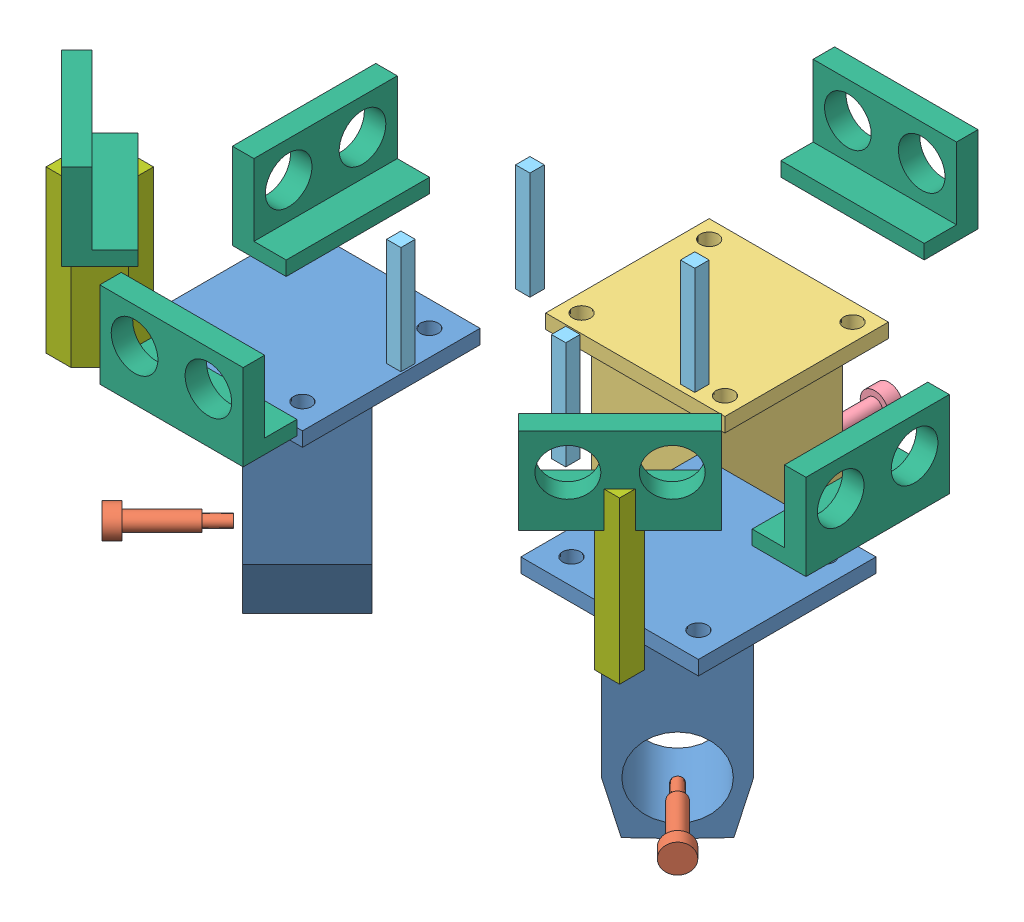
SolidWorks assembly milestone1_3dprints_Final_Assem_v2, configuration Default. Lengths in mm.
Overall size (266.12 155.39 218.29).
163 component instances, 34 part files, 103 mates.
Components (placement in the parent):
- WheelAsm-1: WheelAsm [Default] at (146.9069 -186.0529 168.258) x (-0.210422 -0.954696 0.210422) z (-0.707107 0 -0.707107) size (63.86 60.79 27.6) (hidden)
  - WheelBase-2: WheelBase [Default] at (4.9023 2.731 55.3836) x (1 0 0) z (0 -1 0) size (56.86 5 54.96)
  - BasePlacer-1: BasePlacer [Default] at (4.9023 2.731 58.8836) x (1 0 0) z (0 -1 0) size (28 10 28)
  - RubberWheel-1: RubberWheel [Default] at (4.9023 26.7901 57.8836) x (1 0 0) z (0 -0.999594 -0.028494) size (19 12.5 12.5)
  - RubberWheel-2: RubberWheel [Default] at (-17.9792 10.1657 57.8836) x (0.309017 0.951057 0) z (0.95067 -0.308892 -0.028494) size (19 12.5 12.5)
  - RubberWheel-3: RubberWheel [Default] at (-9.2392 -16.7332 57.8836) x (-0.809017 0.587785 0) z (0.587547 0.808689 -0.028494) size (19 12.5 12.5)
  - RubberWheel-4: RubberWheel [Default] at (19.0439 -16.7332 57.8836) x (-0.809017 -0.587785 0) z (-0.587547 0.808689 -0.028494) size (19 12.5 12.5)
  - RubberWheel-5: RubberWheel [Default] at (27.7839 10.1657 57.8836) x (0.309017 -0.951057 0) z (-0.95067 -0.308892 -0.028494) size (19 12.5 12.5)
  - Rivet-1: Rivet [Default] at (4.9023 -21.269 54.8836) x (1 0 0) z (0 1 0) size (7.46 6.8 7.46)
  - Rivet-2: Rivet [Default] at (27.7277 -4.6854 54.8836) x (0.309017 0.951057 0) z (-0.951057 0.309017 0) size (7.46 6.8 7.46)
  - Rivet-3: Rivet [Default] at (19.0092 22.1474 54.8836) x (-0.809017 0.587785 0) z (-0.587785 -0.809017 0) size (7.46 6.8 7.46)
  - Rivet-4: Rivet [Default] at (-9.2045 22.1474 54.8836) x (-0.809017 -0.587785 0) z (0.587785 -0.809017 0) size (7.46 6.8 7.46)
  - Rivet-5: Rivet [Default] at (-17.923 -4.6854 54.8836) x (0.309017 -0.951057 0) z (0.951057 0.309017 0) size (7.46 6.8 7.46)
  - WheelBase-6: WheelBase [Default] at (4.9023 2.731 67.3836) x (-1 0 0) z (0 1 0) size (56.86 5 54.96)
  - RubberWheel-16: RubberWheel [Default] at (4.9023 -21.3281 69.8836) size (19 12.5 12.5)
  - RubberWheel-17: RubberWheel [Default] at (27.7839 -4.7037 69.8836) x (0.309017 0.951057 0) z (0 0 1) size (19 12.5 12.5)
  - RubberWheel-18: RubberWheel [Default] at (19.0439 22.1953 69.8836) x (-0.809017 0.587785 0) z (0 0 1) size (19 12.5 12.5)
  - RubberWheel-19: RubberWheel [Default] at (-9.2392 22.1953 69.8836) x (-0.809017 -0.587785 0) z (0 0 1) size (19 12.5 12.5)
  - RubberWheel-20: RubberWheel [Default] at (-17.9792 -4.7037 69.8836) x (0.309017 -0.951057 0) z (0 0 1) size (19 12.5 12.5)
  - Rivet-16: Rivet [Default] at (-9.2045 -16.6854 72.8836) x (-0.985624 0.168955 0) z (0.168955 0.985624 0) size (7.46 6.8 7.46)
  - Rivet-17: Rivet [Default] at (19.0092 -16.6854 72.8836) x (-0.46526 -0.885174 0) z (-0.885174 0.46526 0) size (7.46 6.8 7.46)
  - Rivet-18: Rivet [Default] at (27.7277 10.1474 72.8836) x (0.698077 -0.716022 0) z (-0.716022 -0.698077 0) size (7.46 6.8 7.46)
  - Rivet-19: Rivet [Default] at (4.9023 26.731 72.8836) x (0.896695 0.442648 0) z (0.442648 -0.896695 0) size (7.46 6.8 7.46)
  - Rivet-20: Rivet [Default] at (-17.923 10.1474 72.8836) x (-0.143889 0.989594 0) z (0.989594 0.143889 0) size (7.46 6.8 7.46)
  - ShaftConnector-1: ShaftConnector [Default] at (4.9023 2.731 48.8836) x (1 0 0) z (0 -1 0) size (14 27.6 14)
  - Part7^WheelAsm-1: Part7^WheelAsm [Default] at origin (virtual)
  - Part8^WheelAsm-1: Part8^WheelAsm [Default] at origin (virtual)
  - M3HexNut-1: M3HexNut [Default] at (13.9956 7.981 72.8836) x (1 0 0) z (0 0 -1) size (5 5 5)
  - M3HexNut-2: M3HexNut [Default] at (-4.1909 7.981 72.8836) x (-0.5 0.866025 0) z (0 0 -1) size (5 5 5)
  - M3HexNut-3: M3HexNut [Default] at (4.9023 -7.769 72.8836) x (-0.5 -0.866025 0) z (0 0 -1) size (5 5 5)
  - M3HexNut-4: M3HexNut [Default] at (4.9023 -7.769 54.8836) size (5 5 5)
  - M3HexNut-5: M3HexNut [Default] at (13.9956 7.981 54.8836) x (-0.5 0.866025 0) z (0 0 1) size (5 5 5)
  - M3HexNut-6: M3HexNut [Default] at (-4.1909 7.981 54.8836) x (-0.5 -0.866025 0) z (0 0 1) size (5 5 5)
- WheelAsm-2: WheelAsm [Default] at (14.2994 -187.213 -82.1798) x (-0.999988 0.004806 0) z (0 0 1) size (63.86 60.79 27.6) (hidden)
  - WheelBase-2: WheelBase [Default] at (4.9023 2.731 55.3836) x (1 0 0) z (0 -1 0) size (56.86 5 54.96)
  - BasePlacer-1: BasePlacer [Default] at (4.9023 2.731 58.8836) x (1 0 0) z (0 -1 0) size (28 10 28)
  - RubberWheel-1: RubberWheel [Default] at (4.9023 26.7901 57.8836) x (1 0 0) z (0 -0.999594 -0.028494) size (19 12.5 12.5)
  - RubberWheel-2: RubberWheel [Default] at (-17.9792 10.1657 57.8836) x (0.309017 0.951057 0) z (0.95067 -0.308892 -0.028494) size (19 12.5 12.5)
  - RubberWheel-3: RubberWheel [Default] at (-9.2392 -16.7332 57.8836) x (-0.809017 0.587785 0) z (0.587547 0.808689 -0.028494) size (19 12.5 12.5)
  - RubberWheel-4: RubberWheel [Default] at (19.0439 -16.7332 57.8836) x (-0.809017 -0.587785 0) z (-0.587547 0.808689 -0.028494) size (19 12.5 12.5)
  - RubberWheel-5: RubberWheel [Default] at (27.7839 10.1657 57.8836) x (0.309017 -0.951057 0) z (-0.95067 -0.308892 -0.028494) size (19 12.5 12.5)
  - Rivet-1: Rivet [Default] at (4.9023 -21.269 54.8836) x (1 0 0) z (0 1 0) size (7.46 6.8 7.46)
  - Rivet-2: Rivet [Default] at (27.7277 -4.6854 54.8836) x (0.309017 0.951057 0) z (-0.951057 0.309017 0) size (7.46 6.8 7.46)
  - Rivet-3: Rivet [Default] at (19.0092 22.1474 54.8836) x (-0.809017 0.587785 0) z (-0.587785 -0.809017 0) size (7.46 6.8 7.46)
  - Rivet-4: Rivet [Default] at (-9.2045 22.1474 54.8836) x (-0.809017 -0.587785 0) z (0.587785 -0.809017 0) size (7.46 6.8 7.46)
  - Rivet-5: Rivet [Default] at (-17.923 -4.6854 54.8836) x (0.309017 -0.951057 0) z (0.951057 0.309017 0) size (7.46 6.8 7.46)
  - WheelBase-6: WheelBase [Default] at (4.9023 2.731 67.3836) x (-1 0 0) z (0 1 0) size (56.86 5 54.96)
  - RubberWheel-16: RubberWheel [Default] at (4.9023 -21.3281 69.8836) size (19 12.5 12.5)
  - RubberWheel-17: RubberWheel [Default] at (27.7839 -4.7037 69.8836) x (0.309017 0.951057 0) z (0 0 1) size (19 12.5 12.5)
  - RubberWheel-18: RubberWheel [Default] at (19.0439 22.1953 69.8836) x (-0.809017 0.587785 0) z (0 0 1) size (19 12.5 12.5)
  - RubberWheel-19: RubberWheel [Default] at (-9.2392 22.1953 69.8836) x (-0.809017 -0.587785 0) z (0 0 1) size (19 12.5 12.5)
  - RubberWheel-20: RubberWheel [Default] at (-17.9792 -4.7037 69.8836) x (0.309017 -0.951057 0) z (0 0 1) size (19 12.5 12.5)
  - Rivet-16: Rivet [Default] at (-9.2045 -16.6854 72.8836) x (-0.985624 0.168955 0) z (0.168955 0.985624 0) size (7.46 6.8 7.46)
  - Rivet-17: Rivet [Default] at (19.0092 -16.6854 72.8836) x (-0.46526 -0.885174 0) z (-0.885174 0.46526 0) size (7.46 6.8 7.46)
  - Rivet-18: Rivet [Default] at (27.7277 10.1474 72.8836) x (0.698077 -0.716022 0) z (-0.716022 -0.698077 0) size (7.46 6.8 7.46)
  - Rivet-19: Rivet [Default] at (4.9023 26.731 72.8836) x (0.896695 0.442648 0) z (0.442648 -0.896695 0) size (7.46 6.8 7.46)
  - Rivet-20: Rivet [Default] at (-17.923 10.1474 72.8836) x (-0.143889 0.989594 0) z (0.989594 0.143889 0) size (7.46 6.8 7.46)
  - ShaftConnector-1: ShaftConnector [Default] at (4.9023 2.731 48.8836) x (1 0 0) z (0 -1 0) size (14 27.6 14)
  - Part7^WheelAsm-1: Part7^WheelAsm [Default] at origin (virtual)
  - Part8^WheelAsm-1: Part8^WheelAsm [Default] at origin (virtual)
  - M3HexNut-1: M3HexNut [Default] at (13.9956 7.981 72.8836) x (1 0 0) z (0 0 -1) size (5 5 5)
  - M3HexNut-2: M3HexNut [Default] at (-4.1909 7.981 72.8836) x (-0.5 0.866025 0) z (0 0 -1) size (5 5 5)
  - M3HexNut-3: M3HexNut [Default] at (4.9023 -7.769 72.8836) x (-0.5 -0.866025 0) z (0 0 -1) size (5 5 5)
  - M3HexNut-4: M3HexNut [Default] at (4.9023 -7.769 54.8836) size (5 5 5)
  - M3HexNut-5: M3HexNut [Default] at (13.9956 7.981 54.8836) x (-0.5 0.866025 0) z (0 0 1) size (5 5 5)
  - M3HexNut-6: M3HexNut [Default] at (-4.1909 7.981 54.8836) x (-0.5 -0.866025 0) z (0 0 1) size (5 5 5)
- WheelAsm-3: WheelAsm [Default] at (-127.298 -191.8955 165.739) x (0.457087 0.762983 0.457087) z (0.707107 0 -0.707107) size (63.86 60.79 27.6) (hidden)
  - WheelBase-2: WheelBase [Default] at (4.9023 2.731 55.3836) x (1 0 0) z (0 -1 0) size (56.86 5 54.96)
  - BasePlacer-1: BasePlacer [Default] at (4.9023 2.731 58.8836) x (1 0 0) z (0 -1 0) size (28 10 28)
  - RubberWheel-1: RubberWheel [Default] at (4.9023 26.7901 57.8836) x (1 0 0) z (0 -0.999594 -0.028494) size (19 12.5 12.5)
  - RubberWheel-2: RubberWheel [Default] at (-17.9792 10.1657 57.8836) x (0.309017 0.951057 0) z (0.95067 -0.308892 -0.028494) size (19 12.5 12.5)
  - RubberWheel-3: RubberWheel [Default] at (-9.2392 -16.7332 57.8836) x (-0.809017 0.587785 0) z (0.587547 0.808689 -0.028494) size (19 12.5 12.5)
  - RubberWheel-4: RubberWheel [Default] at (19.0439 -16.7332 57.8836) x (-0.809017 -0.587785 0) z (-0.587547 0.808689 -0.028494) size (19 12.5 12.5)
  - RubberWheel-5: RubberWheel [Default] at (27.7839 10.1657 57.8836) x (0.309017 -0.951057 0) z (-0.95067 -0.308892 -0.028494) size (19 12.5 12.5)
  - Rivet-1: Rivet [Default] at (4.9023 -21.269 54.8836) x (1 0 0) z (0 1 0) size (7.46 6.8 7.46)
  - Rivet-2: Rivet [Default] at (27.7277 -4.6854 54.8836) x (0.309017 0.951057 0) z (-0.951057 0.309017 0) size (7.46 6.8 7.46)
  - Rivet-3: Rivet [Default] at (19.0092 22.1474 54.8836) x (-0.809017 0.587785 0) z (-0.587785 -0.809017 0) size (7.46 6.8 7.46)
  - Rivet-4: Rivet [Default] at (-9.2045 22.1474 54.8836) x (-0.809017 -0.587785 0) z (0.587785 -0.809017 0) size (7.46 6.8 7.46)
  - Rivet-5: Rivet [Default] at (-17.923 -4.6854 54.8836) x (0.309017 -0.951057 0) z (0.951057 0.309017 0) size (7.46 6.8 7.46)
  - WheelBase-6: WheelBase [Default] at (4.9023 2.731 67.3836) x (-1 0 0) z (0 1 0) size (56.86 5 54.96)
  - RubberWheel-16: RubberWheel [Default] at (4.9023 -21.3281 69.8836) size (19 12.5 12.5)
  - RubberWheel-17: RubberWheel [Default] at (27.7839 -4.7037 69.8836) x (0.309017 0.951057 0) z (0 0 1) size (19 12.5 12.5)
  - RubberWheel-18: RubberWheel [Default] at (19.0439 22.1953 69.8836) x (-0.809017 0.587785 0) z (0 0 1) size (19 12.5 12.5)
  - RubberWheel-19: RubberWheel [Default] at (-9.2392 22.1953 69.8836) x (-0.809017 -0.587785 0) z (0 0 1) size (19 12.5 12.5)
  - RubberWheel-20: RubberWheel [Default] at (-17.9792 -4.7037 69.8836) x (0.309017 -0.951057 0) z (0 0 1) size (19 12.5 12.5)
  - Rivet-16: Rivet [Default] at (-9.2045 -16.6854 72.8836) x (-0.985624 0.168955 0) z (0.168955 0.985624 0) size (7.46 6.8 7.46)
  - Rivet-17: Rivet [Default] at (19.0092 -16.6854 72.8836) x (-0.46526 -0.885174 0) z (-0.885174 0.46526 0) size (7.46 6.8 7.46)
  - Rivet-18: Rivet [Default] at (27.7277 10.1474 72.8836) x (0.698077 -0.716022 0) z (-0.716022 -0.698077 0) size (7.46 6.8 7.46)
  - Rivet-19: Rivet [Default] at (4.9023 26.731 72.8836) x (0.896695 0.442648 0) z (0.442648 -0.896695 0) size (7.46 6.8 7.46)
  - Rivet-20: Rivet [Default] at (-17.923 10.1474 72.8836) x (-0.143889 0.989594 0) z (0.989594 0.143889 0) size (7.46 6.8 7.46)
  - ShaftConnector-1: ShaftConnector [Default] at (4.9023 2.731 48.8836) x (1 0 0) z (0 -1 0) size (14 27.6 14)
  - Part7^WheelAsm-1: Part7^WheelAsm [Default] at origin (virtual)
  - Part8^WheelAsm-1: Part8^WheelAsm [Default] at origin (virtual)
  - M3HexNut-1: M3HexNut [Default] at (13.9956 7.981 72.8836) x (1 0 0) z (0 0 -1) size (5 5 5)
  - M3HexNut-2: M3HexNut [Default] at (-4.1909 7.981 72.8836) x (-0.5 0.866025 0) z (0 0 -1) size (5 5 5)
  - M3HexNut-3: M3HexNut [Default] at (4.9023 -7.769 72.8836) x (-0.5 -0.866025 0) z (0 0 -1) size (5 5 5)
  - M3HexNut-4: M3HexNut [Default] at (4.9023 -7.769 54.8836) size (5 5 5)
  - M3HexNut-5: M3HexNut [Default] at (13.9956 7.981 54.8836) x (-0.5 0.866025 0) z (0 0 1) size (5 5 5)
  - M3HexNut-6: M3HexNut [Default] at (-4.1909 7.981 54.8836) x (-0.5 -0.866025 0) z (0 0 1) size (5 5 5)
- 6V Motor Spin-1: 6V Motor Spin [Default] at (27.2733 -240.3712 60.9424) x (-0.886104 0.457845 -0.072098) z (0.080946 -0.000295 -0.996718) size (29.63 28.32 78.39) (hidden)
  - Motor no spinny boi-1: Motor no spinny boi [Default] at (39.6165 36.3483 7.7453) x (0.997226 -0.015871 -0.072721) z (0.072098 -0.036799 0.996718) size (24.4 25.49 66.9)
  - Motor spinny boi-1: Motor spinny boi [Default] at (39.6165 36.3483 7.7453) x (0.547957 0.836461 -0.008754) z (0.072098 -0.036799 0.996718) size (3.95 3.95 13.05)
- DC Motor 12V-1: DC Motor 12V [Predeterminado] at (-50.6883 -189.9205 96.5577) x (0.707107 0 0.707107) z (-0.707107 0 0.707107) size (28.03 28 53.5) (hidden)
  - Carcaça12V-1: Carcaça12V [Predeterminado] at (0 0 24.0663) size (28.03 28 32.04)
  - Bucha12V-1: Bucha12V [Predeterminado] at (0 0 26.0163) x (0.994754 0.102295 0) z (0 0 1) size (7 7 0.5)
  - Mancal12V-1: Mancal12V [Predeterminado] at (0 0 -2.9337) x (-1 0 0) z (0 0 -1) size (27.69 28 8)
  - Terminal12V-1: Terminal12V [Predeterminado] at (0 -11.5 -3.9337) x (1 0 0) z (0 1 0) size (2.9 10 0.4)
  - Terminal12V-2: Terminal12V [Predeterminado] at (0 11.5 -3.9337) x (1 0 0) z (0 1 0) size (2.9 10 0.4)
  - Eixo12V-1: Eixo12V [Predeterminado] at (0 0 39.5663) x (-0.33009 -0.943949 0) z (0 0 1) size (21 20.89 51)
  - Enrolamento12V-1: Enrolamento12V [Predeterminado] at (-5.1702 1.808 12.5663) x (0.33009 0.943949 0) z (0 0 1) size (10 3 20)
  - Enrolamento12V-2: Enrolamento12V [Predeterminado] at (1.0194 -5.3815 12.5663) x (-0.982529 -0.186108 0) z (0 0 1) size (10 3 20)
  - Enrolamento12V-3: Enrolamento12V [Predeterminado] at (4.1509 3.5736 12.5663) x (0.652439 -0.757841 0) z (0 0 1) size (10 3 20)
- DC Motor 12V-2: DC Motor 12V [Predeterminado] at (71.1645 -189.9205 98.266) x (-0.300546 0.905176 0.300546) z (0.707107 0 0.707107) size (28.03 28 53.5) (hidden)
  - Carcaça12V-1: Carcaça12V [Predeterminado] at (0 0 24.0663) size (28.03 28 32.04)
  - Bucha12V-1: Bucha12V [Predeterminado] at (0 0 26.0163) x (0.994754 0.102295 0) z (0 0 1) size (7 7 0.5)
  - Mancal12V-1: Mancal12V [Predeterminado] at (0 0 -2.9337) x (-1 0 0) z (0 0 -1) size (27.69 28 8)
  - Terminal12V-1: Terminal12V [Predeterminado] at (0 -11.5 -3.9337) x (1 0 0) z (0 1 0) size (2.9 10 0.4)
  - Terminal12V-2: Terminal12V [Predeterminado] at (0 11.5 -3.9337) x (1 0 0) z (0 1 0) size (2.9 10 0.4)
  - Eixo12V-1: Eixo12V [Predeterminado] at (0 0 39.5663) x (-0.33009 -0.943949 0) z (0 0 1) size (21 20.89 51)
  - Enrolamento12V-1: Enrolamento12V [Predeterminado] at (-5.1702 1.808 12.5663) x (0.33009 0.943949 0) z (0 0 1) size (10 3 20)
  - Enrolamento12V-2: Enrolamento12V [Predeterminado] at (1.0194 -5.3815 12.5663) x (-0.982529 -0.186108 0) z (0 0 1) size (10 3 20)
  - Enrolamento12V-3: Enrolamento12V [Predeterminado] at (4.1509 3.5736 12.5663) x (0.652439 -0.757841 0) z (0 0 1) size (10 3 20)
- Acrylic Plate (square 12 inch) cut version-1: Acrylic Plate (square 12 inch) cut version [Default] at (9.384 -134.5485 57.0478) size (203.2 6.35 203.2) (hidden)
- ScoopClawAssembly-1: ScoopClawAssembly [Default] at (-135.2234 -155.5644 109.464) size (171.3 138.74 218) (hidden)
  - Scooper-1: Scooper [Default] at (144.6073 0.6103 138.0053) x (1 0 0) z (0 0.793599 0.608442) size (152.65 142.24 11.1)
  - Scooper_Base-1: Scooper_Base [Default] at (144.6073 -61.534 72.0438) size (162.56 95.25 144.78)
  - HC-SR04-UltrasonicSensor v7-2: HC-SR04-UltrasonicSensor v7 [Default] at (144.5683 -48.834 48.9638) x (-1 0 0) z (0 0 1) size (45.45 26.2 17.79)
  - Hinge_Joint-1: Hinge_Joint [Default] at (126.8273 46.416 67.8239) x (0 0.774266 0.63286) z (1 0 0) size (8.89 8.89 40.64)
  - Hinge_Part1-1: Hinge_Part1 [Default] at (144.6073 33.716 67.8239) size (35.56 18.62 12.7)
  - Hinge_Part2-1: Hinge_Part2 [Default] at (144.6073 54.4789 74.0056) x (1 0 0) z (0 0.608442 -0.793599) size (25.4 16.08 12.7)
  - 6V Motor Spin-1: 6V Motor Spin [Default] at (231.6559 14.0419 25.1949) x (-0.072098 -0.103157 0.992049) z (-0.996718 0.044149 -0.067847) size (29.63 28.32 78.39) (hidden)
    - Motor no spinny boi-1: Motor no spinny boi [Default] at (39.6165 36.3483 7.7453) x (0.997226 -0.015871 -0.072721) z (0.072098 -0.036799 0.996718) size (24.4 25.49 66.9)
    - Motor spinny boi-1: Motor spinny boi [Default] at (39.6165 36.3483 7.7453) x (0.547957 0.836461 -0.008754) z (0.072098 -0.036799 0.996718) size (3.95 3.95 13.05)
  - Motor Support-1: Motor Support [Default] at (195.4073 27.366 67.8239) size (38.1 54.53 38.1)
- ArduinoMega-1: ArduinoMega [Default] at (9.3459 -119.6895 95.1478) x (0 0 -1) z (0 -1 0) size (107.95 53.42 12.95) (hidden)
- 12V Motor Support-1: 12V Motor Support [Default] at (76.6872 -189.9205 103.7887) x (0.707107 0 0.707107) z (-0.707107 0 0.707107) size (88.99 74.11 88.99)
- 12V Motor Support-2: 12V Motor Support [Default] at (-56.211 -189.9205 102.0804) x (0.707107 0 -0.707107) z (0.707107 0 0.707107) size (88.99 74.11 88.99)
- OmniWheel_Connection Piece-2: OmniWheel_Connection Piece [Default] at (89.7093 -189.9205 116.8107) x (-0.693991 0.19171 0.693991) z (0.707107 0 0.707107) size (10.16 10.16 33.02)
- OmniWheel_Connection Piece-3: OmniWheel_Connection Piece [Default] at (-69.2613 -189.9205 115.1307) x (0.707107 0 0.707107) z (-0.707107 0 0.707107) size (10.16 10.16 33.02)
- 6V Motor Support-1: 6V Motor Support [Default] at (9.384 -189.9205 22.5038) x (0 0 -1) z (1 0 0) size (57.91 74.11 63.5)
- 6V Wheel Connector-1: 6V Wheel Connector [Default] at (9.384 -189.9205 -6.1182) x (-0.104526 0.994522 0) z (0 0 -1) size (10.16 10.16 32.26)
- LED Height Booster-1: LED Height Booster [Default] at (38.594 -83.7485 59.5878) x (-1 0 0) z (0 0 1) size (5.08 38.1 5.08)
- LED Height Booster-2: LED Height Booster [Default] at (-19.826 -121.8485 105.3042) size (5.08 38.1 5.08)
- LED Height Booster-3: LED Height Booster [Default] at (38.594 -83.7485 105.3042) x (-1 0 0) z (0 0 1) size (5.08 38.1 5.08)
- LED Height Booster-4: LED Height Booster [Default] at (-19.826 -121.8485 59.5878) size (5.08 38.1 5.08)
- LightBoard Localization-2: LightBoard Localization [Default] at (9.384 -83.7485 82.4478) x (-1 0 0) z (0 0 -1) size (101.6 13.49 50.8) (hidden)
- HC-SR04-UltrasonicSensor v7-1: HC-SR04-UltrasonicSensor v7 [Default] at (-40.996 -204.3985 158.4278) x (-1 0 0) z (0 0 1) size (45.45 26.2 17.79) (hidden)
- HC-SR04-UltrasonicSensor v7-2: HC-SR04-UltrasonicSensor v7 [Default] at (59.764 -204.3985 158.4278) x (-1 0 0) z (0 0 1) size (45.45 26.2 17.79) (hidden)
- US_Support-2: US_Support [Default] at (103.364 -123.1185 67.2078) x (0 0 -1) z (1 0 0) size (50.8 30.48 19.05)
- US_Support-3: US_Support [Default] at (-84.596 -123.1185 67.2078) x (0 0 1) z (-1 0 0) size (50.8 30.48 19.05)
- BatteryRemodeled-2: BatteryRemodeled [Default] at (34.784 -76.1031 -0.1022) x (-1 0 0) z (0 0 1) size (64.52 53.39 25.65) (hidden)
- US_Support-4: US_Support [Default] at (9.384 -123.1185 -36.9322) x (-1 0 0) z (0 0 -1) size (50.8 30.48 19.05)
- US_Support-5: US_Support [Default] at (-47.766 -123.1185 151.0278) size (50.8 30.48 19.05)
- HC-SR04-UltrasonicSensor v7-3: HC-SR04-UltrasonicSensor v7 [Default] at (98.064 -110.4185 67.1688) x (0 0 1) z (1 0 0) size (45.45 26.2 17.79) (hidden)
- HC-SR04-UltrasonicSensor v7-4: HC-SR04-UltrasonicSensor v7 [Default] at (9.345 -110.4185 -31.6322) x (1 0 0) z (0 0 -1) size (45.45 26.2 17.79) (hidden)
- HC-SR04-UltrasonicSensor v7-5: HC-SR04-UltrasonicSensor v7 [Default] at (-79.296 -110.4185 67.1688) x (0 0 -1) z (-1 0 0) size (45.45 26.2 17.79) (hidden)
- corner_support-1: corner_support [Default] at (-82.691 -128.1985 149.1228) size (19.05 57.15 19.05)
- US_Support-6: US_Support [Default] at (-84.1338 -78.6685 150.386) x (0.707107 0 0.707107) z (-0.707107 0 0.707107) size (50.8 30.48 19.05)
- HC-SR04-UltrasonicSensor v7-6: HC-SR04-UltrasonicSensor v7 [Default] at (-80.3586 -65.9685 146.6659) x (-0.707107 0 -0.707107) z (-0.707107 0 0.707107) size (45.45 26.2 17.79) (hidden)
- HC-SR04-UltrasonicSensor v7-7: HC-SR04-UltrasonicSensor v7 [Default] at (-47.805 -110.4185 145.7278) x (-1 0 0) z (0 0 1) size (45.45 26.2 17.79) (hidden)
- corner_support-2: corner_support [Default] at (101.459 -128.1985 149.1228) x (0 0 -1) z (1 0 0) size (19.05 57.15 19.05)
- US_Support-7: US_Support [Default] at (102.9017 -78.6685 150.386) x (0.707107 0 -0.707107) z (0.707107 0 0.707107) size (50.8 30.48 19.05)
- HC-SR04-UltrasonicSensor v7-8: HC-SR04-UltrasonicSensor v7 [Default] at (99.1265 -65.9685 146.6659) x (-0.707107 0 0.707107) z (0.707107 0 0.707107) size (45.45 26.2 17.79) (hidden)
Mates (geometry in assembly coordinates):
- Coincident3: coincident: plane of Acrylic Plate (square 12 inch) cut version-1 through (9.384 -128.1985 57.0478) normal (0 1 0); plane of ScoopClawAssembly-1/Scooper_Base-1 through (9.384 -128.1985 181.5078) normal (0 -1 0)
- Coincident4: coincident: plane of Acrylic Plate (square 12 inch) cut version-1 through (-92.216 -128.1985 158.6478) normal (0 0 1); plane of ScoopClawAssembly-1/Scooper_Base-1 through (9.384 -217.0985 158.6478) normal (0 0 -1)
- Distance4: distance = 0.508 mm: plane of ScoopClawAssembly-1/Scooper_Base-1 through (9.384 -121.8485 181.5078) normal (0 1 0); plane of ArduinoMega-1 through (-17.3622 -121.3405 44.3478) normal (0 -1 0)
- Distance6: distance = 12.7 mm: plane of ArduinoMega-1 through (36.054 -121.3405 44.3478) normal (0 0 -1); plane of ScoopClawAssembly-1/Scooper_Base-1 through (41.134 -121.8485 57.0478) normal (0 0 -1)
- Distance7: distance = 5.08 mm: plane of ArduinoMega-1 through (36.054 -121.3405 145.9478) normal (1 0 0); plane of ScoopClawAssembly-1/Scooper_Base-1 through (41.134 -166.2985 158.6478) normal (1 0 0)
- Coincident23: coincident: plane of Acrylic Plate (square 12 inch) cut version-1 through (9.384 -134.5485 57.0478) normal (0 -1 0); plane of 12V Motor Support-1 through (76.6872 -134.5485 103.7887) normal (0 1 0)
- Coincident29: coincident: plane of Acrylic Plate (square 12 inch) cut version-1 through (9.384 -134.5485 57.0478) normal (0 -1 0); plane of 12V Motor Support-2 through (-56.211 -134.5485 102.0804) normal (0 1 0)
- Concentric1: concentric: cylinder of DC Motor 12V-1/Carcaça12V-1 through (-47.1996 -189.9205 93.069) axis (-0.707107 0 0.707107) radius 14; cylinder of 12V Motor Support-2 through (-134.5188 -189.9205 180.3882) axis (0.707107 0 -0.707107) radius 13.9872
- Coincident31: coincident: plane of DC Motor 12V-1/Carcaça12V-1 through (-67.7057 -189.9205 113.5751) normal (-0.707107 0 0.707107); plane of 12V Motor Support-2 through (-54.2353 -139.6285 127.0455) normal (-0.707107 0 0.707107)
- Coincident32: coincident: plane of DC Motor 12V-2/Carcaça12V-1 through (88.1819 -189.9205 115.2834) normal (0.707107 0 0.707107); plane of 12V Motor Support-1 through (74.7115 -139.6285 128.7538) normal (0.707107 0 0.707107)
- Concentric2: concentric: cylinder of DC Motor 12V-2/Carcaça12V-1 through (67.6758 -189.9205 94.7773) axis (0.707107 0 0.707107) radius 14; cylinder of 12V Motor Support-1 through (-1.6206 -189.9205 25.4808) axis (0.707107 0 0.707107) radius 13.9872
- Concentric4: concentric: circle of WheelAsm-1/ShaftConnector-1; circle of DC Motor 12V-2/Eixo12V-1
- Coincident36: coincident: plane of WheelAsm-1/ShaftConnector-1 through (89.9497 -189.9205 117.0512) normal (-0.707107 0 -0.707107); plane of DC Motor 12V-2/Carcaça12V-1 through (89.9497 -189.9205 117.0512) normal (0.707107 0 0.707107)
- Concentric8: concentric: circle of WheelAsm-1/ShaftConnector-1; circle of OmniWheel_Connection Piece-2
- Coincident39: coincident: plane of WheelAsm-1/ShaftConnector-1 through (109.4658 -189.9205 136.5673) normal (0.707107 0 0.707107); plane of OmniWheel_Connection Piece-2 through (109.4658 -189.9205 136.5673) normal (-0.707107 0 -0.707107)
- Distance9: distance = 69.85 mm: plane of ScoopClawAssembly-1/Scooper_Base-1 through (-22.366 -128.1985 158.6478) normal (-1 0 0); plane of Acrylic Plate (square 12 inch) cut version-1 through (-92.216 -128.1985 158.6478) normal (-1 0 0)
- Concentric9: concentric: circle of WheelAsm-3/ShaftConnector-1; circle of DC Motor 12V-1/Eixo12V-1
- Coincident42: coincident: plane of WheelAsm-3/ShaftConnector-1 through (-89.0179 -189.9205 134.8873) normal (-0.707107 0 0.707107); plane of OmniWheel_Connection Piece-3 through (-89.0179 -189.9205 134.8873) normal (0.707107 0 -0.707107)
- Concentric10: concentric: circle of WheelAsm-3/ShaftConnector-1; circle of OmniWheel_Connection Piece-3
- Coincident43: coincident: plane of DC Motor 12V-1/Bucha12V-1 through (-69.2613 -189.9205 115.1307) normal (-0.707107 0 0.707107); plane of OmniWheel_Connection Piece-3 through (-69.2613 -189.9205 115.1307) normal (0.707107 0 -0.707107)
- Coincident45: coincident: plane of Acrylic Plate (square 12 inch) cut version-1 through (9.384 -134.5485 57.0478) normal (0 -1 0); plane of 6V Motor Support-1 through (9.384 -134.5485 22.5038) normal (0 1 0)
- Concentric11: concentric: circle of 6V Motor Spin-1/Motor no spinny boi-1; circle of 6V Motor Support-1
- Coincident48: coincident: plane of 6V Motor Spin-1/Motor no spinny boi-1 through (9.384 -189.9205 -2.8962) normal (0 0 -1); plane of 6V Motor Support-1 through (28.434 -139.6285 -2.8962) normal (0 0 -1)
- Concentric13: concentric: circle of WheelAsm-2/ShaftConnector-1; circle of 6V Motor Support-1
- Coincident49: coincident: plane of WheelAsm-2/ShaftConnector-1 through (9.384 -189.9205 -5.6962) normal (0 0 1); plane of 6V Motor Spin-1/Motor no spinny boi-1 through (9.384 -189.9205 -5.6962) normal (0 0 -1)
- Concentric14: concentric: circle of WheelAsm-2/ShaftConnector-1; circle of 6V Wheel Connector-1
- Coincident51: coincident: plane of 6V Motor Spin-1/Motor spinny boi-1 through (9.2246 -188.4038 -5.9462) normal (-0.104526 0.994522 0); plane of 6V Wheel Connector-1 through (9.2246 -188.4038 -16.0242) normal (0.104526 -0.994522 0)
- Coincident52: coincident: plane of WheelAsm-2/ShaftConnector-1 through (9.384 -189.9205 -33.2962) normal (0 0 -1); plane of 6V Wheel Connector-1 through (9.384 -189.9205 -33.2962) normal (0 0 1)
- Distance13: distance = 38.1 mm: plane of 6V Motor Support-1 through (41.134 -134.5485 -6.4522) normal (0 0 -1); plane of Acrylic Plate (square 12 inch) cut version-1 through (-92.216 -128.1985 -44.5522) normal (0 0 -1)
- Distance15: distance = 69.85 mm: plane of 6V Motor Support-1 through (41.134 -134.5485 -6.4522) normal (1 0 0); plane of Acrylic Plate (square 12 inch) cut version-1 through (110.984 -128.1985 158.6478) normal (1 0 0)
- Coincident73: coincident: plane of ScoopClawAssembly-1/Scooper_Base-1 through (9.384 -121.8485 181.5078) normal (0 1 0); plane of LED Height Booster-1 through (38.594 -121.8485 59.5878) normal (0 -1 0)
- Coincident74: coincident: plane of ScoopClawAssembly-1/Scooper_Base-1 through (41.134 -121.8485 57.0478) normal (0 0 -1); plane of LED Height Booster-1 through (41.134 -121.8485 57.0478) normal (0 0 -1)
- Coincident75: coincident: plane of ScoopClawAssembly-1/Scooper_Base-1 through (41.134 -166.2985 158.6478) normal (1 0 0); plane of LED Height Booster-1 through (41.134 -121.8485 62.1278) normal (1 0 0)
- Coincident76: coincident: plane of ScoopClawAssembly-1/Scooper_Base-1 through (41.134 -121.8485 57.0478) normal (0 0 -1); plane of LED Height Booster-4 through (-22.366 -83.7485 57.0478) normal (0 0 -1)
- Coincident77: coincident: plane of ScoopClawAssembly-1/Scooper_Base-1 through (9.384 -121.8485 181.5078) normal (0 1 0); plane of LED Height Booster-4 through (-19.826 -121.8485 59.5878) normal (0 -1 0)
- Coincident78: coincident: plane of ScoopClawAssembly-1/Scooper_Base-1 through (-22.366 -128.1985 158.6478) normal (-1 0 0); plane of LED Height Booster-4 through (-22.366 -83.7485 62.1278) normal (-1 0 0)
- Coincident79: coincident: plane of ScoopClawAssembly-1/Scooper_Base-1 through (9.384 -121.8485 181.5078) normal (0 1 0); plane of LED Height Booster-3 through (38.594 -121.8485 105.3042) normal (0 -1 0)
- Coincident80: coincident: plane of LED Height Booster-1 through (41.134 -121.8485 62.1278) normal (1 0 0); plane of LED Height Booster-3 through (41.134 -121.8485 107.8442) normal (1 0 0)
- Distance21: distance = 55.4736 mm: plane of LED Height Booster-3 through (41.134 -121.8485 102.7642) normal (0 0 -1); plane of ScoopClawAssembly-1/Motor Support-1 through (41.134 -123.1185 158.2378) normal (0 0 -1)
- Coincident82: coincident: plane of LED Height Booster-2 through (-22.366 -83.7485 102.7642) normal (0 0 -1); plane of LED Height Booster-3 through (41.134 -121.8485 102.7642) normal (0 0 -1)
- Coincident83: coincident: plane of ScoopClawAssembly-1/Scooper_Base-1 through (9.384 -121.8485 181.5078) normal (0 1 0); plane of LED Height Booster-2 through (-19.826 -121.8485 105.3042) normal (0 -1 0)
- Coincident84: coincident: plane of ScoopClawAssembly-1/Scooper_Base-1 through (-22.366 -128.1985 158.6478) normal (-1 0 0); plane of LED Height Booster-2 through (-22.366 -83.7485 107.8442) normal (-1 0 0)
- Coincident85: coincident: plane of LED Height Booster-1 through (38.594 -83.7485 59.5878) normal (0 1 0); plane of LightBoard Localization-2 through (9.384 -83.7485 82.4478) normal (0 -1 0)
- Coincident88: coincident: plane of LED Height Booster-4 through (-22.366 -83.7485 57.0478) normal (0 0 -1); plane of LightBoard Localization-2 through (60.184 -77.3985 57.0478) normal (0 0 -1)
- Distance22: distance = 19.05 mm: plane of LightBoard Localization-2 through (-41.416 -77.3985 57.0478) normal (-1 0 0); plane of LED Height Booster-4 through (-22.366 -83.7485 62.1278) normal (-1 0 0)
- Coincident91: coincident: plane of ScoopClawAssembly-1/Scooper_Base-1 through (9.384 -217.0985 163.7278) normal (0 0 -1); plane of HC-SR04-UltrasonicSensor v7-2 through (59.764 -211.7841 163.7278) normal (0 0 1)
- Parallel9: parallel: plane of ScoopClawAssembly-1/Scooper_Base-1 through (9.384 -217.0985 181.5078) normal (0 -1 0); plane of HC-SR04-UltrasonicSensor v7-2 through (37.039 -214.3985 158.4278) normal (0 -1 0)
- Parallel10: parallel: plane of ScoopClawAssembly-1/Scooper_Base-1 through (9.384 -217.0985 181.5078) normal (0 -1 0); plane of HC-SR04-UltrasonicSensor v7-1 through (-63.721 -214.3985 158.4278) normal (0 -1 0)
- Coincident94: coincident: plane of ScoopClawAssembly-1/Scooper_Base-1 through (9.384 -217.0985 163.7278) normal (0 0 -1); plane of HC-SR04-UltrasonicSensor v7-1 through (-40.996 -211.7841 163.7278) normal (0 0 1)
- Coincident95: coincident: plane of Acrylic Plate (square 12 inch) cut version-1 through (110.984 -128.1985 158.6478) normal (1 0 0); plane of US_Support-2 through (110.984 -123.1185 67.2078) normal (1 0 0)
- Coincident96: coincident: plane of Acrylic Plate (square 12 inch) cut version-1 through (9.384 -128.1985 57.0478) normal (0 1 0); plane of US_Support-2 through (103.364 -128.1985 67.2078) normal (0 -1 0)
- Distance23: distance = 86.36 mm: plane of US_Support-2 through (110.984 -123.1185 41.8078) normal (0 0 -1); plane of Acrylic Plate (square 12 inch) cut version-1 through (-92.216 -128.1985 -44.5522) normal (0 0 -1)
- Coincident98: coincident: plane of US_Support-2 through (110.984 -123.1185 92.6078) normal (0 0 1); plane of US_Support-3 through (-92.216 -123.1185 92.6078) normal (0 0 1)
- Coincident99: coincident: plane of Acrylic Plate (square 12 inch) cut version-1 through (9.384 -128.1985 57.0478) normal (0 1 0); plane of US_Support-3 through (-84.596 -128.1985 67.2078) normal (0 -1 0)
- Coincident100: coincident: plane of Acrylic Plate (square 12 inch) cut version-1 through (-92.216 -128.1985 158.6478) normal (-1 0 0); plane of US_Support-3 through (-92.216 -123.1185 67.2078) normal (-1 0 0)
- Coincident101: coincident: plane of Acrylic Plate (square 12 inch) cut version-1 through (9.384 -128.1985 57.0478) normal (0 1 0); plane of BatteryRemodeled-2 through (34.784 -128.1985 -0.1022) normal (0 -1 0)
- Distance24: distance = 38.1 mm: line of BatteryRemodeled-2 through (-4.078 -128.1731 -6.4522) axis (1 0 0); line of Acrylic Plate (square 12 inch) cut version-1 through (47.484 -128.1985 -44.5522) axis (-1 0 0)
- Distance25: distance = 69.85 mm: line of BatteryRemodeled-2 through (41.134 -128.1731 -0.1022) axis (0 0 1); line of Acrylic Plate (square 12 inch) cut version-1 through (110.984 -128.1985 158.6478) axis (0 0 -1)
- Coincident106: coincident: plane of Acrylic Plate (square 12 inch) cut version-1 through (-92.216 -128.1985 -44.5522) normal (0 0 -1); plane of US_Support-4 through (9.384 -123.1185 -44.5522) normal (0 0 -1)
- Coincident107: coincident: plane of Acrylic Plate (square 12 inch) cut version-1 through (9.384 -128.1985 57.0478) normal (0 1 0); plane of US_Support-4 through (9.384 -128.1985 -36.9322) normal (0 -1 0)
- Distance26: distance = 76.2 mm: plane of US_Support-4 through (-16.016 -123.1185 -44.5522) normal (-1 0 0); plane of Acrylic Plate (square 12 inch) cut version-1 through (-92.216 -128.1985 158.6478) normal (-1 0 0)
- Coincident109: coincident: plane of Acrylic Plate (square 12 inch) cut version-1 through (9.384 -128.1985 57.0478) normal (0 1 0); plane of US_Support-5 through (-47.766 -128.1985 151.0278) normal (0 -1 0)
- Distance27: distance = 19.05 mm: plane of US_Support-5 through (-73.166 -123.1185 158.6478) normal (-1 0 0); plane of Acrylic Plate (square 12 inch) cut version-1 through (-92.216 -128.1985 158.6478) normal (-1 0 0)
- Coincident111: coincident: plane of Acrylic Plate (square 12 inch) cut version-1 through (-92.216 -128.1985 158.6478) normal (0 0 1); plane of US_Support-5 through (-47.766 -123.1185 158.6478) normal (0 0 1)
- Concentric20: concentric: cylinder of HC-SR04-UltrasonicSensor v7-5 through (-80.896 -110.4185 80.2888) axis (-1 0 0) radius 8; cylinder of US_Support-3 through (-92.216 -110.4185 80.2888) axis (1 0 0) radius 8.2697
- Parallel16: parallel: plane of US_Support-3 through (-92.216 -97.7185 41.8078) normal (0 1 0); plane of HC-SR04-UltrasonicSensor v7-5 through (-79.296 -100.4185 89.8938) normal (0 1 0)
- Coincident114: coincident: plane of US_Support-3 through (-84.596 -123.1185 67.2078) normal (1 0 0); plane of HC-SR04-UltrasonicSensor v7-5 through (-84.596 -117.8041 67.1688) normal (-1 0 0)
- Concentric21: concentric: cylinder of US_Support-2 through (110.984 -110.4185 80.2888) axis (-1 0 0) radius 8.2697; cylinder of HC-SR04-UltrasonicSensor v7-3 through (99.664 -110.4185 80.2888) axis (1 0 0) radius 8
- Parallel17: parallel: plane of US_Support-2 through (103.364 -123.1185 67.2078) normal (0 1 0); plane of HC-SR04-UltrasonicSensor v7-3 through (98.064 -120.4185 89.8938) normal (0 -1 0)
- Coincident116: coincident: plane of US_Support-2 through (103.364 -123.1185 67.2078) normal (-1 0 0); plane of HC-SR04-UltrasonicSensor v7-3 through (103.364 -117.8041 67.1688) normal (1 0 0)
- Concentric23: concentric: cylinder of US_Support-4 through (22.465 -110.4185 -44.5522) axis (0 0 1) radius 8.2697; cylinder of HC-SR04-UltrasonicSensor v7-4 through (22.465 -110.4185 -33.2322) axis (0 0 -1) radius 8
- Parallel18: parallel: plane of US_Support-4 through (9.384 -123.1185 -36.9322) normal (0 1 0); plane of HC-SR04-UltrasonicSensor v7-4 through (32.07 -120.4185 -31.6322) normal (0 -1 0)
- Coincident118: coincident: plane of US_Support-4 through (9.384 -123.1185 -36.9322) normal (0 0 1); plane of HC-SR04-UltrasonicSensor v7-4 through (9.345 -117.8041 -36.9322) normal (0 0 -1)
- Coincident119: coincident: plane of Acrylic Plate (square 12 inch) cut version-1 through (-92.216 -128.1985 158.6478) normal (-1 0 0); plane of corner_support-1 through (-92.216 -83.7485 158.6478) normal (-1 0 0)
- Coincident120: coincident: plane of Acrylic Plate (square 12 inch) cut version-1 through (9.384 -128.1985 57.0478) normal (0 1 0); plane of corner_support-1 through (-82.691 -128.1985 149.1228) normal (0 -1 0)
- Coincident121: coincident: plane of Acrylic Plate (square 12 inch) cut version-1 through (-92.216 -128.1985 158.6478) normal (0 0 1); plane of corner_support-1 through (-92.216 -83.7485 158.6478) normal (0 0 1)
- Coincident135: coincident: plane of corner_support-1 through (-86.6483 -71.0485 158.6478) normal (0.707107 0 -0.707107); plane of US_Support-6 through (-89.522 -78.6685 155.7741) normal (-0.707107 0 0.707107)
- Concentric24: concentric: cylinder of US_Support-6 through (-98.7716 -65.9685 146.5245) axis (0.707107 0 -0.707107) radius 8.2697; cylinder of HC-SR04-UltrasonicSensor v7-6 through (-90.7672 -65.9685 138.52) axis (-0.707107 0 0.707107) radius 8
- Parallel23: parallel: plane of US_Support-6 through (-84.1338 -78.6685 150.386) normal (0 1 0); plane of HC-SR04-UltrasonicSensor v7-6 through (-96.4276 -75.9685 130.5969) normal (0 -1 0)
- Coincident138: coincident: plane of US_Support-6 through (-84.1338 -78.6685 150.386) normal (0.707107 0 -0.707107); plane of HC-SR04-UltrasonicSensor v7-6 through (-84.1062 -73.3541 150.4136) normal (-0.707107 0 0.707107)
- Concentric25: concentric: cylinder of US_Support-5 through (-34.685 -110.4185 158.6478) axis (0 0 -1) radius 8.2697; cylinder of HC-SR04-UltrasonicSensor v7-7 through (-34.685 -110.4185 147.3278) axis (0 0 1) radius 8
- Parallel24: parallel: plane of US_Support-5 through (-73.166 -97.7185 158.6478) normal (0 1 0); plane of HC-SR04-UltrasonicSensor v7-7 through (-25.08 -100.4185 145.7278) normal (0 1 0)
- Coincident140: coincident: plane of US_Support-5 through (-47.766 -123.1185 151.0278) normal (0 0 -1); plane of HC-SR04-UltrasonicSensor v7-7 through (-47.805 -117.8041 151.0278) normal (0 0 1)
- Coincident142: coincident: plane of Acrylic Plate (square 12 inch) cut version-1 through (110.984 -128.1985 158.6478) normal (1 0 0); plane of corner_support-2 through (110.984 -83.7485 158.6478) normal (1 0 0)
- Coincident143: coincident: plane of Acrylic Plate (square 12 inch) cut version-1 through (9.384 -128.1985 57.0478) normal (0 1 0); plane of corner_support-2 through (101.459 -128.1985 149.1228) normal (0 -1 0)
- Coincident144: coincident: plane of Acrylic Plate (square 12 inch) cut version-1 through (-92.216 -128.1985 158.6478) normal (0 0 1); plane of corner_support-2 through (110.984 -83.7485 158.6478) normal (0 0 1)
- Coincident145: coincident: plane of corner_support-1 through (-82.691 -83.7485 149.1228) normal (0 1 0); plane of US_Support-6 through (-84.1338 -83.7485 150.386) normal (0 -1 0)
- Distance35: distance = 21.59 mm: line of corner_support-1 through (-92.216 -71.0485 153.0801) axis (0 -1 0); line of US_Support-6 through (-107.4825 -53.2685 137.8136) axis (0 -1 0)
- Coincident148: coincident: plane of corner_support-2 through (101.459 -83.7485 149.1228) normal (0 1 0); plane of US_Support-7 through (102.9017 -83.7485 150.386) normal (0 -1 0)
- Coincident150: coincident: plane of corner_support-2 through (110.984 -71.0485 153.0801) normal (-0.707107 0 -0.707107); plane of US_Support-7 through (108.2899 -78.6685 155.7741) normal (0.707107 0 0.707107)
- Distance36: distance = 21.59 mm: line of US_Support-7 through (126.2504 -83.7485 137.8136) axis (0 1 0); line of corner_support-2 through (110.984 -71.0485 153.0801) axis (0 -1 0)
- Concentric26: concentric: cylinder of US_Support-7 through (117.5395 -65.9685 146.5245) axis (-0.707107 0 -0.707107) radius 8.2697; cylinder of HC-SR04-UltrasonicSensor v7-8 through (109.5351 -65.9685 138.52) axis (0.707107 0 0.707107) radius 8
- Parallel25: parallel: plane of US_Support-7 through (102.9017 -78.6685 150.386) normal (0 1 0); plane of HC-SR04-UltrasonicSensor v7-8 through (83.0575 -75.9685 162.7349) normal (0 -1 0)
- Coincident153: coincident: plane of US_Support-7 through (102.9017 -78.6685 150.386) normal (-0.707107 0 -0.707107); plane of HC-SR04-UltrasonicSensor v7-8 through (102.8742 -73.3541 150.4136) normal (0.707107 0 0.707107)
- Concentric27: concentric: cylinder of ScoopClawAssembly-1/Scooper_Base-1 through (72.884 -204.3985 171.3478) axis (0 0 -1) radius 8.2697; cylinder of HC-SR04-UltrasonicSensor v7-2 through (72.884 -204.3985 160.0278) axis (0 0 1) radius 8
- Concentric28: concentric: cylinder of ScoopClawAssembly-1/Scooper_Base-1 through (-54.116 -204.3985 171.3478) axis (0 0 -1) radius 8.2697; cylinder of HC-SR04-UltrasonicSensor v7-1 through (-54.116 -204.3985 160.0278) axis (0 0 1) radius 8
- Coincident157: coincident: plane of Acrylic Plate (square 12 inch) cut version-1 through (9.384 -134.5485 57.0478) normal (0 -1 0); plane of 12V Motor Support-1 through (76.6872 -134.5485 103.7887) normal (0 1 0)
- Coincident167: coincident: plane of Acrylic Plate (square 12 inch) cut version-1 through (9.384 -134.5485 57.0478) normal (0 -1 0); plane of 12V Motor Support-1 through (76.6872 -134.5485 103.7887) normal (0 1 0)
- Coincident168: coincident: plane of Acrylic Plate (square 12 inch) cut version-1 through (9.384 -134.5485 57.0478) normal (0 -1 0); plane of 12V Motor Support-2 through (-56.211 -134.5485 102.0804) normal (0 1 0)
- Distance40: distance = 27.94 mm: plane of 12V Motor Support-2 through (-29.2918 -134.5485 130.7078) normal (0 0 1); plane of Acrylic Plate (square 12 inch) cut version-1 through (-92.216 -128.1985 158.6478) normal (0 0 1)
- Coincident171: coincident: plane of Acrylic Plate (square 12 inch) cut version-1 through (-92.216 -128.1985 158.6478) normal (-1 0 0); plane of 12V Motor Support-2 through (-92.216 -134.5485 130.7078) normal (-1 0 0)
- Distance41: distance = 27.94 mm: plane of 12V Motor Support-1 through (110.984 -134.5485 130.7078) normal (0 0 1); plane of Acrylic Plate (square 12 inch) cut version-1 through (-92.216 -128.1985 158.6478) normal (0 0 1)
- Coincident173: coincident: plane of Acrylic Plate (square 12 inch) cut version-1 through (110.984 -128.1985 158.6478) normal (1 0 0); plane of 12V Motor Support-1 through (110.984 -134.5485 67.7836) normal (1 0 0)
